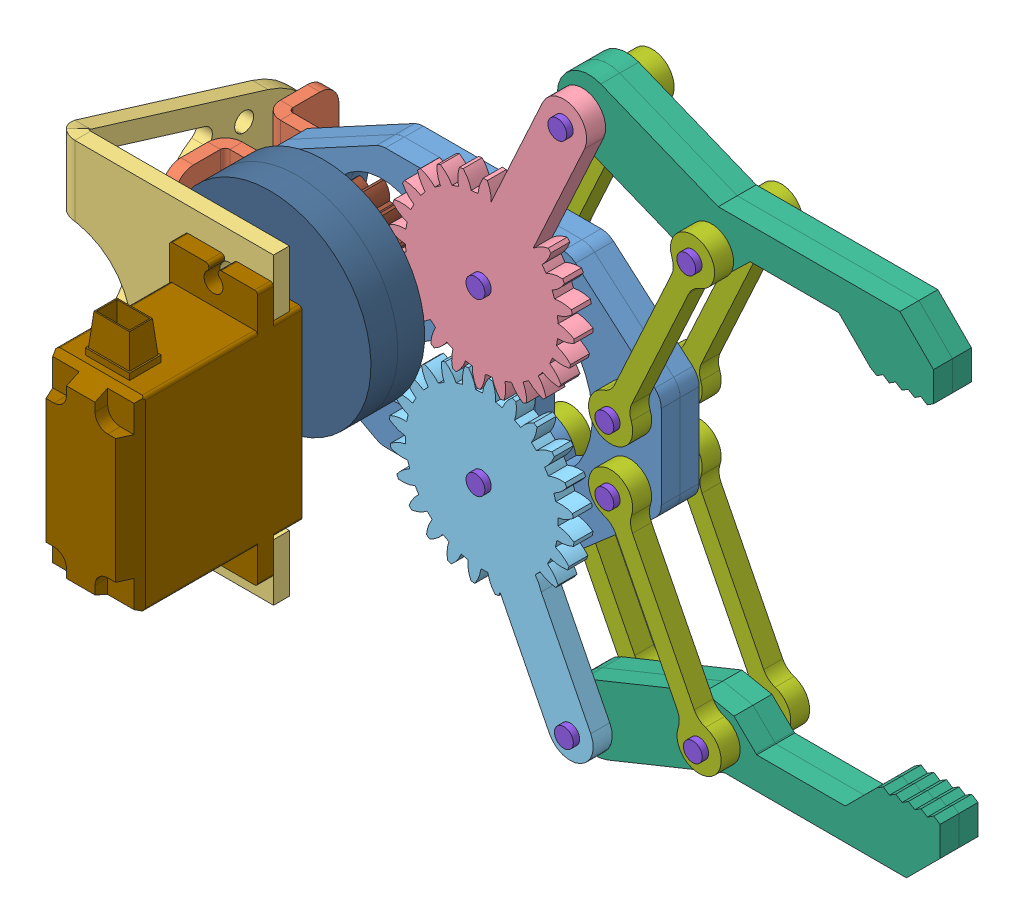
SolidWorks assembly Gripper_New, configuration Default. Lengths in mm.
Overall size (118.35 115.85 64.02).
32 component instances, 11 part files, 3 mates.
Components (placement in the parent):
- Assem4-1: Assem4 [Default] at (13.5 -5.5 -37.5997) x (0 1 0) z (-1 0 0) size (115.85 40.52 118.35) (flexible)
  - grip3-1: grip3 [Predeterminado] at origin size (41 3 62)
  - grip3-2: grip3 [Predeterminado] at (0 3 0) size (41 3 62)
  - grip51-1: grip51 [Default] at (0 6.5 -7) x (-1 0 0) z (0 0 -1) size (20 10 14)
  - grip51-2: grip51 [Default] at (0 -3.5 -7) x (1 0 0) z (0 0 -1) size (20 10 14)
  - grip2-1: grip2 [Predeterminado] at (-2.5 -23.5172 -25.1763) x (1 0 0) z (0 0 -1) size (48.01 40.52 34.68)
  - GEAR11-1: GEAR11 [Metric - Spur gear 1.125M 24T 20PA 3FW ---S24N75H50L1.5N] at (13.5 -5.5 -37.5997) x (0 1 0) z (-0.908476 0 0.417936) size (3 29.07 49.19)
  - GEAR21-2: GEAR21 [Metric - Spur gear 1.125M 24T 20PA 3FW ---S24N75H50L1.5N] at (-13.5 -5.5 -37.5997) x (0 1 0) z (0.956415 0 0.292011) size (3 29.07 48.73)
  - grip41-1: grip41 [Default] at (38.9026 1.5 -44.0456) x (0 -1 0) z (0.375 0 0.927025) size (3 20.79 60.37)
  - grip41-2: grip41 [Default] at (-38.4018 -1.5 -45.0831) x (0 1 0) z (-0.375 0 0.927025) size (3 20.79 60.37)
  - grip41-3: grip41 [Default] at (-38.4018 1.5 -45.0831) x (0 1 0) z (-0.375 0 0.927025) size (3 20.79 60.37)
  - grip41-4: grip41 [Default] at (38.9026 4.5 -44.0456) x (0 -1 0) z (0.375 0 0.927025) size (3 20.79 60.37)
  - grip11-1: grip11 [Default] at (-41.1619 5.5 -51.5932) x (0.89232 0 0.451404) z (-0.451404 0 0.89232) size (38 3 7)
  - grip11-2: grip11 [Default] at (13.5 5.5 -37.5997) x (0.908476 0 -0.417936) z (0.417936 0 0.908476) size (38 3 7)
  - grip11-3: grip11 [Default] at (5.25 5.5 -57.9943) x (0.908476 0 -0.417936) z (0.417936 0 0.908476) size (38 3 7)
  - grip11-4: grip11 [Default] at (5.25 -5.5 -57.9943) x (0.908476 0 -0.417936) z (0.417936 0 0.908476) size (38 3 7)
  - grip11-5: grip11 [Default] at (-32.9119 -5.5 -71.9878) x (0.89232 0 0.451404) z (-0.451404 0 0.89232) size (38 3 7)
  - grip11-6: grip11 [Default] at (-32.9119 5.5 -71.9878) x (0.89232 0 0.451404) z (-0.451404 0 0.89232) size (38 3 7)
  - pin1-1: pin1 [Default] at (-32.9119 1.5 -71.9878) size (3 16 3)
  - pin1-2: pin1 [Default] at (-41.1619 1.5 -51.5932) size (3 16 3)
  - pin1-3: pin1 [Default] at (-5.25 1.5 -57.9943) size (3 16 3)
  - pin1-4: pin1 [Default] at (-13.5 1.5 -37.5997) size (3 16 3)
  - pin1-5: pin1 [Default] at (33.4128 1.5 -70.9503) size (3 16 3)
  - pin1-6: pin1 [Default] at (41.6628 1.5 -50.5557) size (3 16 3)
  - pin1-7: pin1 [Default] at (5.25 1.5 -57.9943) size (3 16 3)
  - pin1-8: pin1 [Default] at (13.5 1.5 -37.5997) size (3 16 3)
- gripper servo-1: gripper servo [Default] at (31.6763 -8 -2.0825) x (0 1 0) z (-1 0 0) size (48.24 52.75 36.62) (flexible)
  - servo_small-1: servo_small [Predeterminado] at origin size (40.9 36.75 14)
  - circular_coupling-1: circular_coupling [Default] at (9.73 16.3 0.39) x (0.987622 0 0.15685) z (-0.15685 0 0.987622) size (32 4.25 32)
  - circular_coupling-2: circular_coupling [Default] at (9.73 24.8 0.39) x (-0.987622 0 -0.15685) z (-0.15685 0 0.987622) size (32 4.25 32)
  - small gear_new2-4: small gear_new2 [Metric - Spur gear 1.125M 12T 20PA 10FW ---S12N75H50L3N] at (9.73 35 0.39) x (0 -1 0) z (0.774402 0 -0.632694) size (10 15.31 15.31)
  - pin1-1: pin1 [Default] at (9.73 30.75 0.39) x (0.917663 0 0.397359) z (-0.397359 0 0.917663) size (3 16 3)
Mates (geometry in assembly coordinates):
- Coincident1: coincident anti-aligned: circle of Assem4-1/grip2-1; circle of gripper servo-1/servo_small-1
- Coincident2: coincident anti-aligned: circle of Assem4-1/grip2-1; circle of gripper servo-1/servo_small-1
- GearMate2: gear = 2 : 1 mm: circle of gripper servo-1/small gear_new2-4; circle of Assem4-1/GEAR11-1
